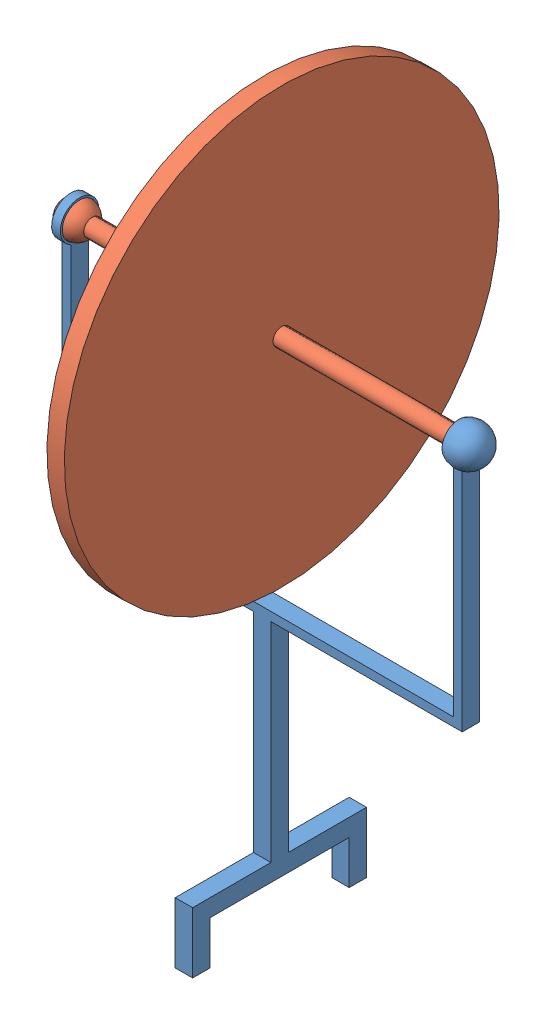
SolidWorks assembly Assemblage1, configuration Défaut. Lengths in mm.
Overall size (98.5 186.8 137.59).
2 component instances, 2 part files, 2 mates.
Components (placement in the parent):
- Pied-1: Pied [Défaut] at (-9.276 -51.237 122.5) size (95.98 122.5 40)
- Disque-1: Disque [Défaut] at (-8.7953 52.763 122.5) x (1 0 0) z (0 0.851358 -0.524586) size (98 100 100)
Mates (geometry in assembly coordinates):
- Coaxiale3: concentric: sphere of Pied-1; sphere of Disque-1
- Parallèle1: parallel anti-aligned: line of Pied-1 through (34.724 -1.237 120.5) axis (-1 0 0); cylinder of Disque-1 through (-8.7953 52.763 122.5) axis (1 0 0) radius 2
